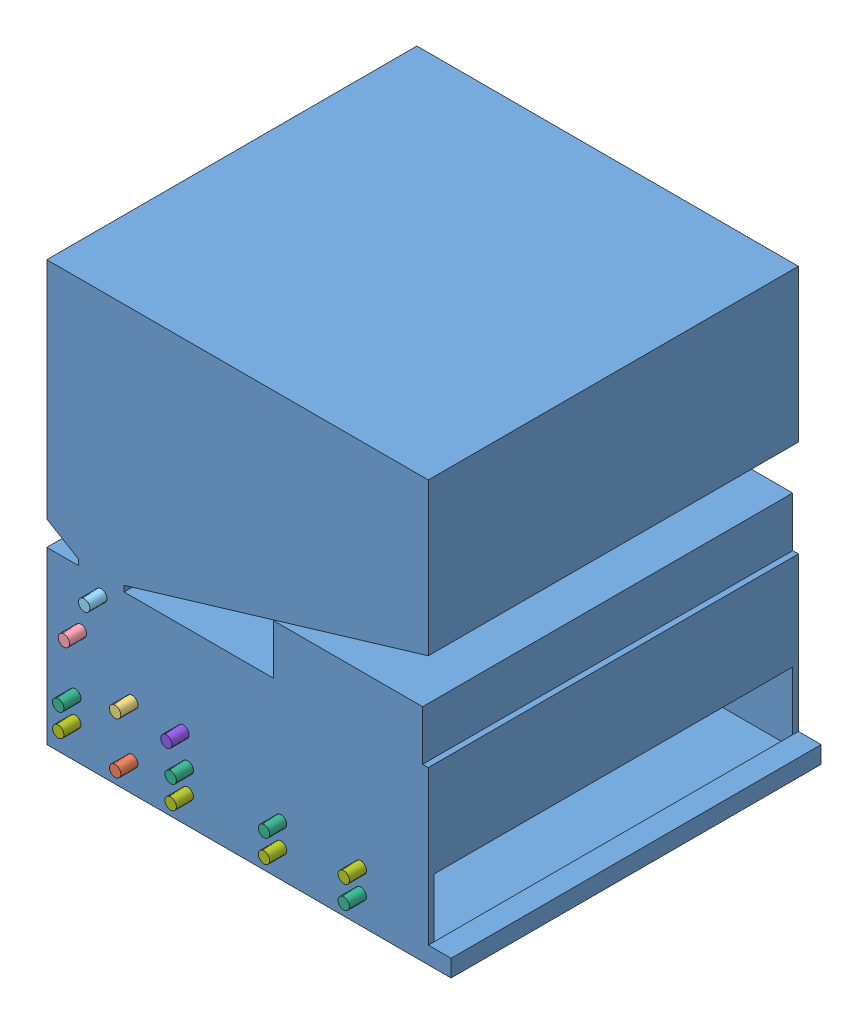
SolidWorks assembly final printer, configuration Default. Lengths in mm.
Overall size (365 368.75 355).
14 component instances, 8 part files, 32 mates.
Components (placement in the parent):
- printer case-1: printer case [Default] at (85.0272 72.0996 448.7887) x (0 0 1) z (-1 0 0) size (325 368.75 365)
- transfer roller-1: transfer roller [Default] at (-7.4728 97.0996 291.2887) x (0.116646 0.993174 0) z (0 0 1) size (20 20 355)
- OPC drum-1: OPC drum [Default] at (-7.4728 142.0996 291.2887) x (0.24529 0.96945 0) z (0 0 1) size (70 70 355)
- developer roller-1: developer roller [Default] at (-52.4728 173.7223 291.2887) x (0.071281 0.997456 0) z (0 0 1) size (40 40 355)
- sponge roller-1: sponge roller [Default] at (-34.6311 209.5228 291.2887) size (40 40 355)
- bring roller 1-1: bring roller 1 [Default] at (-57.4728 122.0996 291.2887) size (20 20 355)
- bring roller 2-1: bring roller 2 [Default] at (-57.4728 102.0996 291.2887) size (20 20 355)
- charging roller-2: charging roller [Default] at (37.5271 142.035 291.2887) size (20 20 355)
- bring roller 1-2: bring roller 1 [Default] at (41.3043 116.6871 291.2887) size (20 20 355)
- bring roller 2-2: bring roller 2 [Default] at (41.3043 96.6871 291.2887) size (20 20 355)
- bring roller 1-3: bring roller 1 [Default] at (123.2434 116.6871 291.2887) size (20 20 355)
- bring roller 2-3: bring roller 2 [Default] at (123.2434 96.6871 291.2887) size (20 20 355)
- bring roller 1-4: bring roller 1 [Default] at (193.2676 96.6871 291.2887) size (20 20 355)
- bring roller 2-4: bring roller 2 [Default] at (193.2676 116.6871 291.2887) size (20 20 355)
Mates (geometry in assembly coordinates):
- Concentric1: concentric anti-aligned: cylinder of printer case-1 through (-7.4728 97.0996 272.1466) axis (0 0 1) radius 5; cylinder of transfer roller-1 through (-7.4728 97.0996 626.2887) axis (0 0 -1) radius 5
- Concentric2: concentric aligned: cylinder of printer case-1 through (-7.4728 97.0996 272.1466) axis (0 0 1) radius 5; cylinder of transfer roller-1 through (-7.4728 97.0996 271.2887) axis (0 0 1) radius 5
- Coincident2: coincident anti-aligned: plane of printer case-1 through (252.5272 222.0996 291.2887) normal (0 0 1); plane of transfer roller-1 through (-7.4728 97.0996 291.2887) normal (0 0 -1)
- Concentric3: concentric anti-aligned: cylinder of printer case-1 through (-7.4728 142.0996 272.1466) axis (0 0 1) radius 5; cylinder of OPC drum-1 through (-7.4728 142.0996 626.2887) axis (0 0 -1) radius 5
- Concentric4: concentric aligned: cylinder of printer case-1 through (-7.4728 142.0996 272.1466) axis (0 0 1) radius 5; cylinder of OPC drum-1 through (-7.4728 142.0996 271.2887) axis (0 0 1) radius 5
- Coincident3: coincident anti-aligned: plane of printer case-1 through (252.5272 222.0996 291.2887) normal (0 0 1); plane of OPC drum-1 through (-7.4728 142.0996 291.2887) normal (0 0 -1)
- Concentric5: concentric anti-aligned: cylinder of printer case-1 through (-52.4728 173.7223 272.1466) axis (0 0 1) radius 5; cylinder of developer roller-1 through (-52.4728 173.7223 626.2887) axis (0 0 -1) radius 5
- Concentric6: concentric aligned: cylinder of printer case-1 through (-52.4728 173.7223 272.1466) axis (0 0 1) radius 5; cylinder of developer roller-1 through (-52.4728 173.7223 271.2887) axis (0 0 1) radius 5
- Coincident4: coincident anti-aligned: plane of printer case-1 through (252.5272 222.0996 291.2887) normal (0 0 1); plane of developer roller-1 through (-52.4728 173.7223 291.2887) normal (0 0 -1)
- Coincident5: coincident anti-aligned: plane of printer case-1 through (252.5272 222.0996 291.2887) normal (0 0 1); plane of sponge roller-1 through (-34.6311 209.5228 291.2887) normal (0 0 -1)
- Concentric7: concentric anti-aligned: cylinder of printer case-1 through (-34.6311 209.5228 272.1466) axis (0 0 1) radius 5; cylinder of sponge roller-1 through (-34.6311 209.5228 626.2887) axis (0 0 -1) radius 5
- Coincident6: coincident anti-aligned: plane of printer case-1 through (252.5272 222.0996 291.2887) normal (0 0 1); plane of charging roller-1 through (33.4415 123.3641 291.2887) normal (0 0 -1)
- Concentric8: concentric anti-aligned: cylinder of printer case-1 through (37.5271 142.035 272.1466) axis (0 0 1) radius 5; cylinder of charging roller-1 through (33.4415 123.3641 626.2887) axis (0 0 -1) radius 5
- Coincident7: coincident anti-aligned: plane of printer case-1 through (252.5272 222.0996 291.2887) normal (0 0 1); plane of bring roller 1-1 through (-57.4728 122.0996 291.2887) normal (0 0 -1)
- Concentric9: concentric anti-aligned: cylinder of printer case-1 through (-57.4728 122.0996 272.1466) axis (0 0 1) radius 5; cylinder of bring roller 1-1 through (-57.4728 122.0996 626.2887) axis (0 0 -1) radius 5
- Coincident8: coincident anti-aligned: plane of printer case-1 through (252.5272 222.0996 291.2887) normal (0 0 1); plane of bring roller 2-1 through (-57.4728 102.0996 291.2887) normal (0 0 -1)
- Concentric10: concentric anti-aligned: cylinder of printer case-1 through (-57.4728 102.0996 272.1466) axis (0 0 1) radius 5; cylinder of bring roller 2-1 through (-57.4728 102.0996 626.2887) axis (0 0 -1) radius 5
- Coincident9: coincident anti-aligned: plane of printer case-1 through (252.5272 222.0996 291.2887) normal (0 0 1); plane of charging roller-2 through (37.5271 142.035 291.2887) normal (0 0 -1)
- Concentric11: concentric anti-aligned: cylinder of printer case-1 through (37.5271 142.035 272.1466) axis (0 0 1) radius 5; cylinder of charging roller-2 through (37.5271 142.035 626.2887) axis (0 0 -1) radius 5
- Concentric12: concentric anti-aligned: cylinder of printer case-1 through (37.5271 142.035 272.1466) axis (0 0 1) radius 5; cylinder of charging roller-2 through (37.5271 142.035 626.2887) axis (0 0 -1) radius 5
- Coincident10: coincident anti-aligned: plane of printer case-1 through (252.5272 222.0996 291.2887) normal (0 0 1); plane of bring roller 1-2 through (41.3043 116.6871 291.2887) normal (0 0 -1)
- Coincident11: coincident anti-aligned: plane of printer case-1 through (252.5272 222.0996 291.2887) normal (0 0 1); plane of bring roller 2-2 through (41.3043 96.6871 291.2887) normal (0 0 -1)
- Concentric13: concentric anti-aligned: cylinder of printer case-1 through (41.3043 116.6871 272.1466) axis (0 0 1) radius 5; cylinder of bring roller 1-2 through (41.3043 116.6871 626.2887) axis (0 0 -1) radius 5
- Concentric14: concentric anti-aligned: cylinder of printer case-1 through (41.3043 96.6871 272.1466) axis (0 0 1) radius 5; cylinder of bring roller 2-2 through (41.3043 96.6871 626.2887) axis (0 0 -1) radius 5
- Coincident12: coincident anti-aligned: plane of printer case-1 through (252.5272 222.0996 291.2887) normal (0 0 1); plane of bring roller 1-3 through (123.2434 116.6871 291.2887) normal (0 0 -1)
- Coincident13: coincident anti-aligned: plane of printer case-1 through (252.5272 222.0996 291.2887) normal (0 0 1); plane of bring roller 2-3 through (123.2434 96.6871 291.2887) normal (0 0 -1)
- Concentric15: concentric anti-aligned: cylinder of printer case-1 through (123.2434 116.6871 272.1466) axis (0 0 1) radius 5; cylinder of bring roller 1-3 through (123.2434 116.6871 626.2887) axis (0 0 -1) radius 5
- Concentric16: concentric anti-aligned: cylinder of printer case-1 through (123.2434 96.6871 272.1466) axis (0 0 1) radius 5; cylinder of bring roller 2-3 through (123.2434 96.6871 626.2887) axis (0 0 -1) radius 5
- Coincident14: coincident anti-aligned: plane of printer case-1 through (252.5272 222.0996 291.2887) normal (0 0 1); plane of bring roller 1-4 through (193.2676 96.6871 291.2887) normal (0 0 -1)
- Coincident15: coincident anti-aligned: plane of printer case-1 through (252.5272 222.0996 291.2887) normal (0 0 1); plane of bring roller 2-4 through (193.2676 116.6871 291.2887) normal (0 0 -1)
- Concentric17: concentric anti-aligned: cylinder of printer case-1 through (193.2676 96.6871 272.1466) axis (0 0 1) radius 5; cylinder of bring roller 1-4 through (193.2676 96.6871 626.2887) axis (0 0 -1) radius 5
- Concentric18: concentric anti-aligned: cylinder of printer case-1 through (193.2676 116.6871 272.1466) axis (0 0 1) radius 5; cylinder of bring roller 2-4 through (193.2676 116.6871 626.2887) axis (0 0 -1) radius 5
